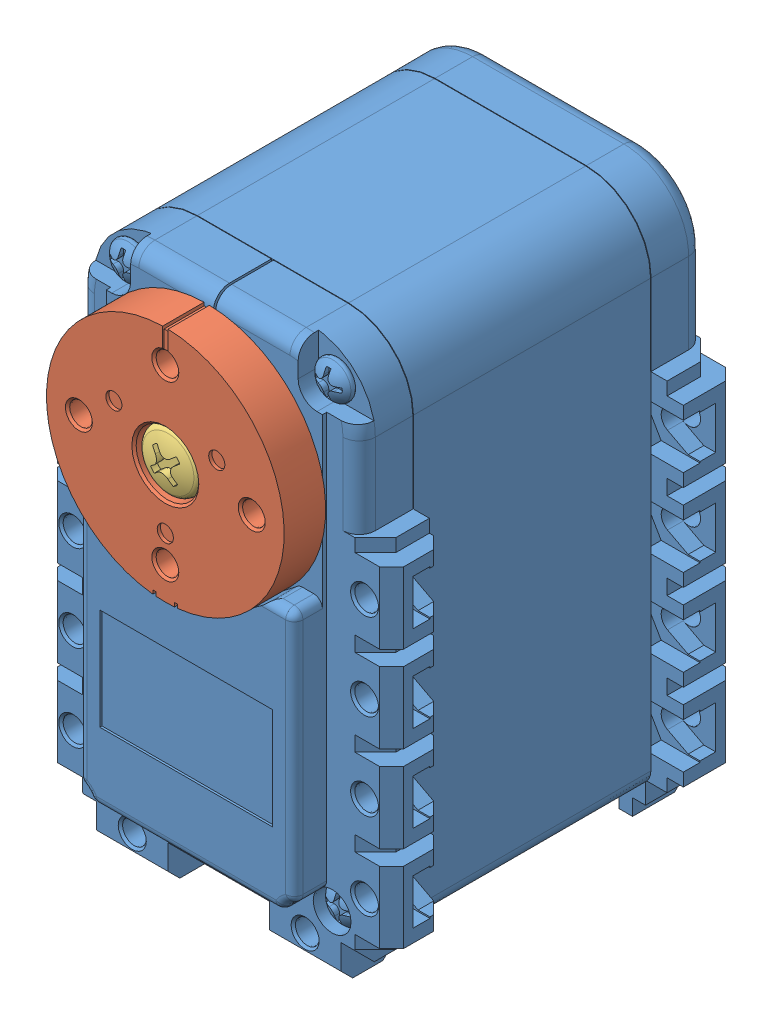
SolidWorks assembly AX-12A, configuration Défaut. Lengths in mm.
Overall size (32 50.04 40.32).
3 component instances, 3 part files, 5 mates.
Components (placement in the parent):
- dynamixel_AXseries-1: dynamixel_AXseries [Défaut] at (-52.3097 25.1945 -0.0173) size (32 50.04 38.37)
- AX12_horn-1: AX12_horn [Défaut] at (-52.3097 25.1945 19.0827) x (0 1 0) z (0 0 1) size (22 22 6.7)
- BHS_M2_6X8-1: BHS_M2_6X8 [Défaut] at (-52.3097 25.1945 19.5327) x (0.628847 -0.777529 0) z (-0.777529 -0.628847 0) size (5.5 9.6 5.5)
Mates (geometry in assembly coordinates):
- Concentric2: concentric aligned: cylinder of dynamixel_AXseries-1 through (-52.3097 25.1945 17.8827) axis (0 0 1) radius 2.9; cylinder of AX12_horn-1 through (-52.3097 25.1945 21.7827) axis (0 0 1) radius 2.9
- Angle1: planar angle = 0 rad anti-aligned: plane of AX12_horn-1 through (-51.3847 26.1079 22.5387) normal (-1 0 0); plane of dynamixel_AXseries-1 through (-51.8597 26.5729 17.8827) normal (1 0 0)
- Coincident3: coincident anti-aligned: plane of dynamixel_AXseries-1 through (-52.3097 25.1945 17.8827) normal (0 0 1); plane of AX12_horn-1 through (-52.3097 25.1945 17.8827) normal (0 0 -1)
- Concentric3: concentric anti-aligned: cylinder of dynamixel_AXseries-1 through (-52.3097 25.1945 -2.3423) axis (0 0 1) radius 1.15; cylinder of BHS_M2_6X8-1 through (-52.3097 25.1945 21.6127) axis (0 0 -1) radius 1.3
- Coincident4: coincident anti-aligned: plane of AX12_horn-1 through (-52.3097 25.1945 19.5327) normal (0 0 1); plane of BHS_M2_6X8-1 through (-52.3097 25.1945 19.5327) normal (0 0 -1)
